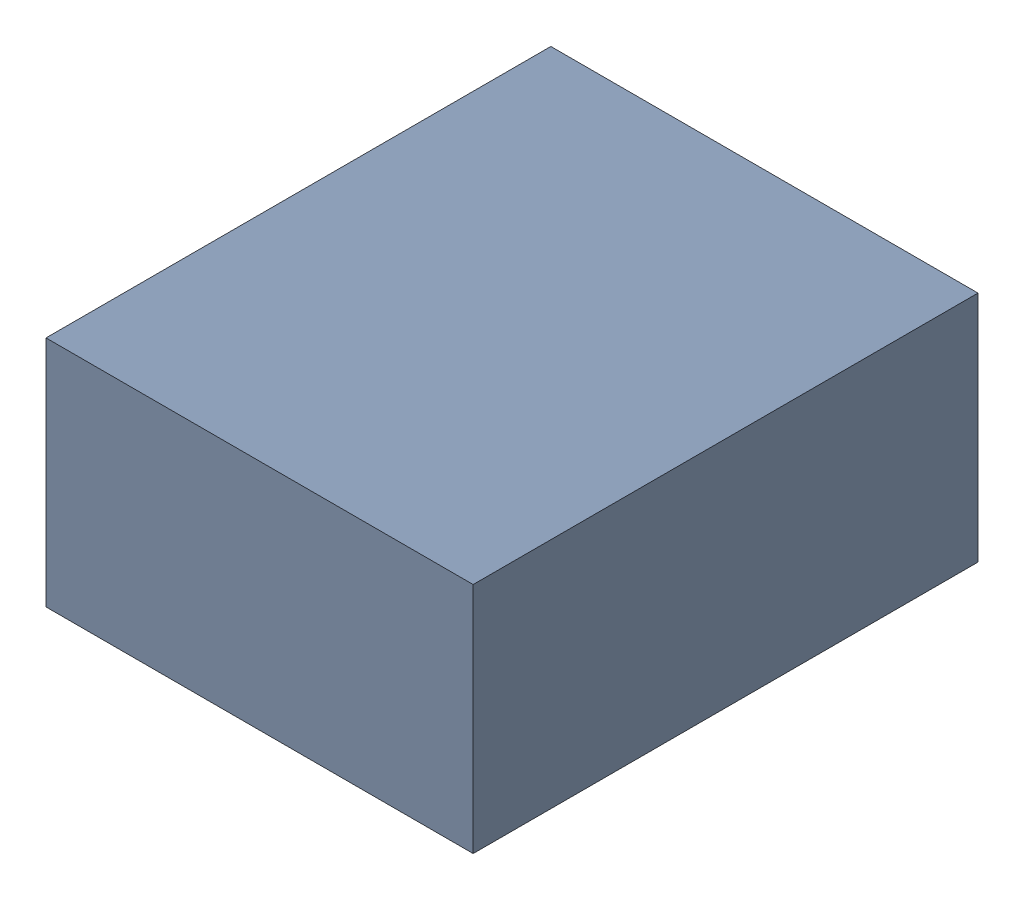
SolidWorks assembly C24_TDA1, configuration Standard. Lengths in mm.
Overall size (1.1 0.6 1.3).
2 component instances, 1 part files, 0 mates.
Components (placement in the parent):
- 885542240-1: 885542240 [Standard] at (-0.92 44.64 0) size (1.1 0.6 1.3)
  - Extruded_28-1: Extruded_28 [Standard] at origin size (1.1 0.6 1.3)
